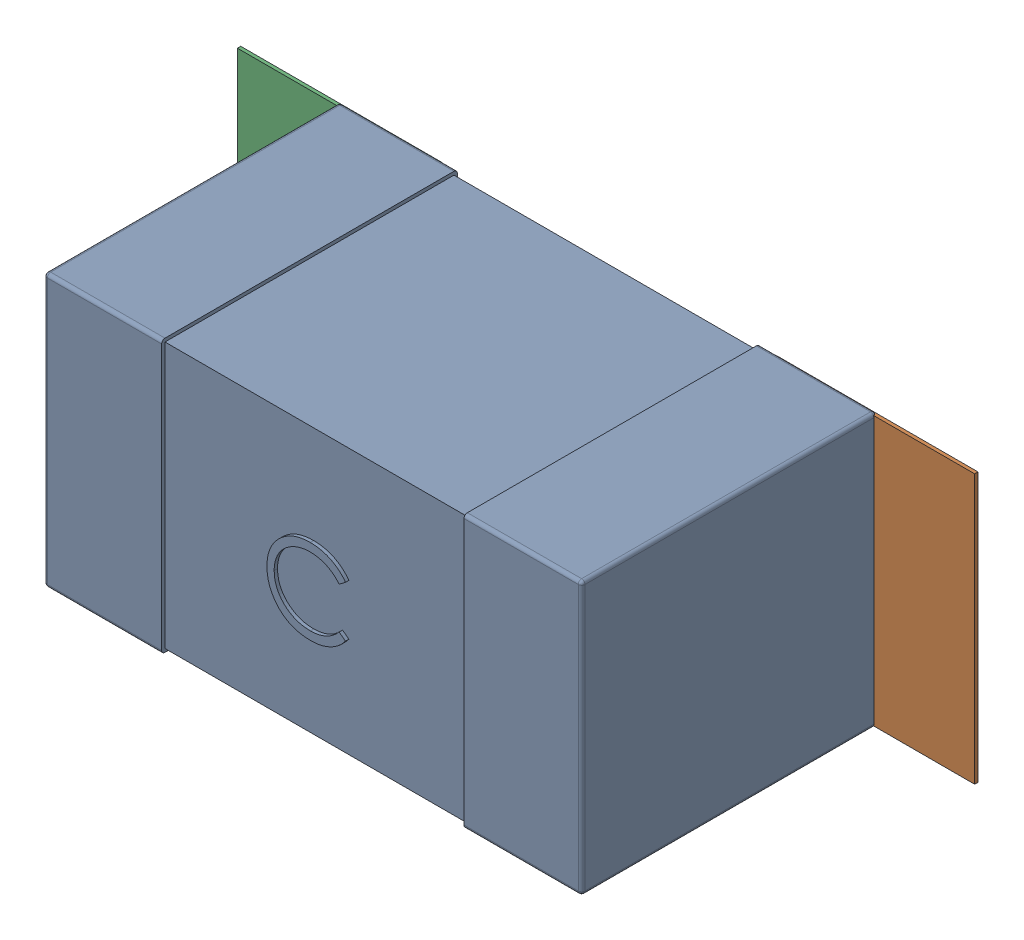
SolidWorks assembly C38, configuration Défaut. Lengths in mm.
Overall size (2.19 0.81 0.88).
5 component instances, 2 part files, 0 mates.
Components (placement in the parent):
- 0603_C-1: 0603_C [Défaut] at (5.3513 -11.6838 0) x (1 0 0) z (0 0 1) size (1.6 0.81 0.88)
- 6634915696-1: 6634915696 [Défaut] at (6.6013 -11.6839 0) size (0.6 0.8 0.01)
  - Extruded_497-1: Extruded_497 [Défaut] at origin size (0.6 0.8 0.01)
- 6634915696-2: 6634915696 [Défaut] at (5.0064 -11.6839 0) size (0.6 0.8 0.01)
  - Extruded_497-1: Extruded_497 [Défaut] at origin size (0.6 0.8 0.01)
